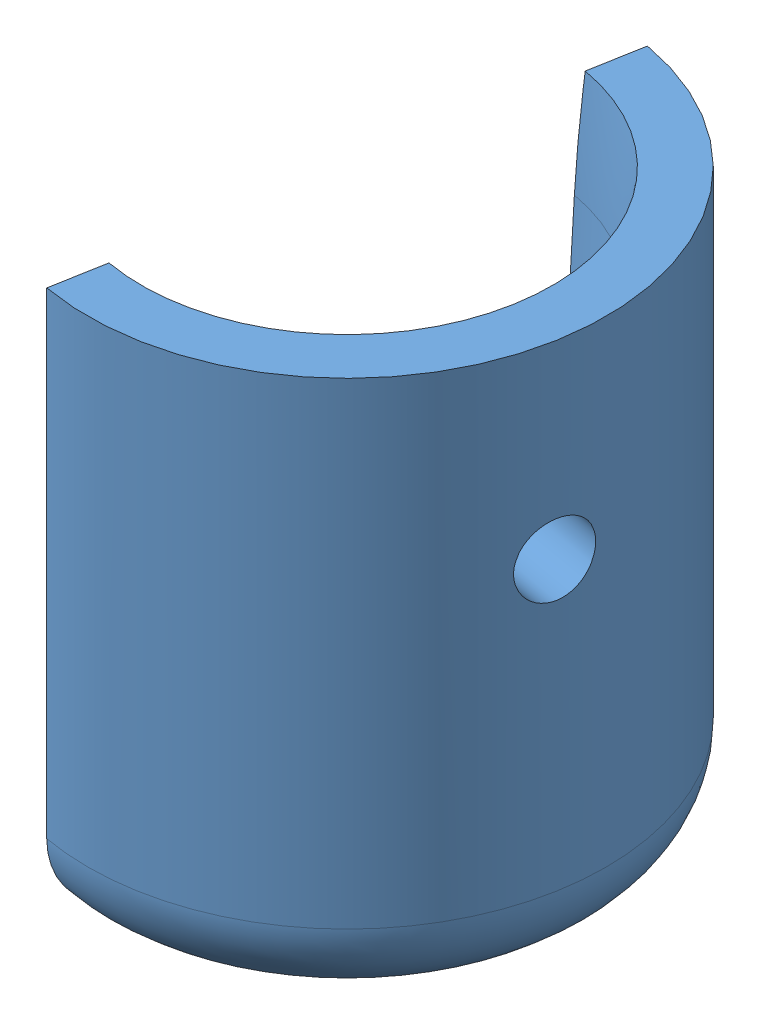
SolidWorks assembly Old Sleeve Assembly, configuration Default. Lengths in mm.
Overall size (33.12 52.07 51.9).
2 component instances, 2 part files, 2 mates.
Components (placement in the parent):
- Tibial End - Copy-2: Tibial End - Copy [Default] at (77.0383 -24.6389 116.5485) (suppressed, hidden)
- Sleeve-2: Sleeve [Default] at (77.0383 -24.789 116.5485) x (0.984502 0 0.175374) z (-0.175374 0 0.984502) size (26.42 52.07 48.26)
Mates (geometry in assembly coordinates):
- Parallel1: parallel: cylinder of assembly; cone of Tibial End - Copy-2 through (77.0383 -24.6389 116.5485) axis (0 -1 0); cylinder of Sleeve-2 through (77.0383 -26.059 116.5485) axis (0 -1 0) radius 24.13
- Concentric1: concentric: cylinder of assembly; cone of Tibial End - Copy-2 through (77.0383 -24.6389 116.5485) axis (0 -1 0); cylinder of Sleeve-2 through (77.0383 -26.059 116.5485) axis (0 -1 0) radius 24.13
